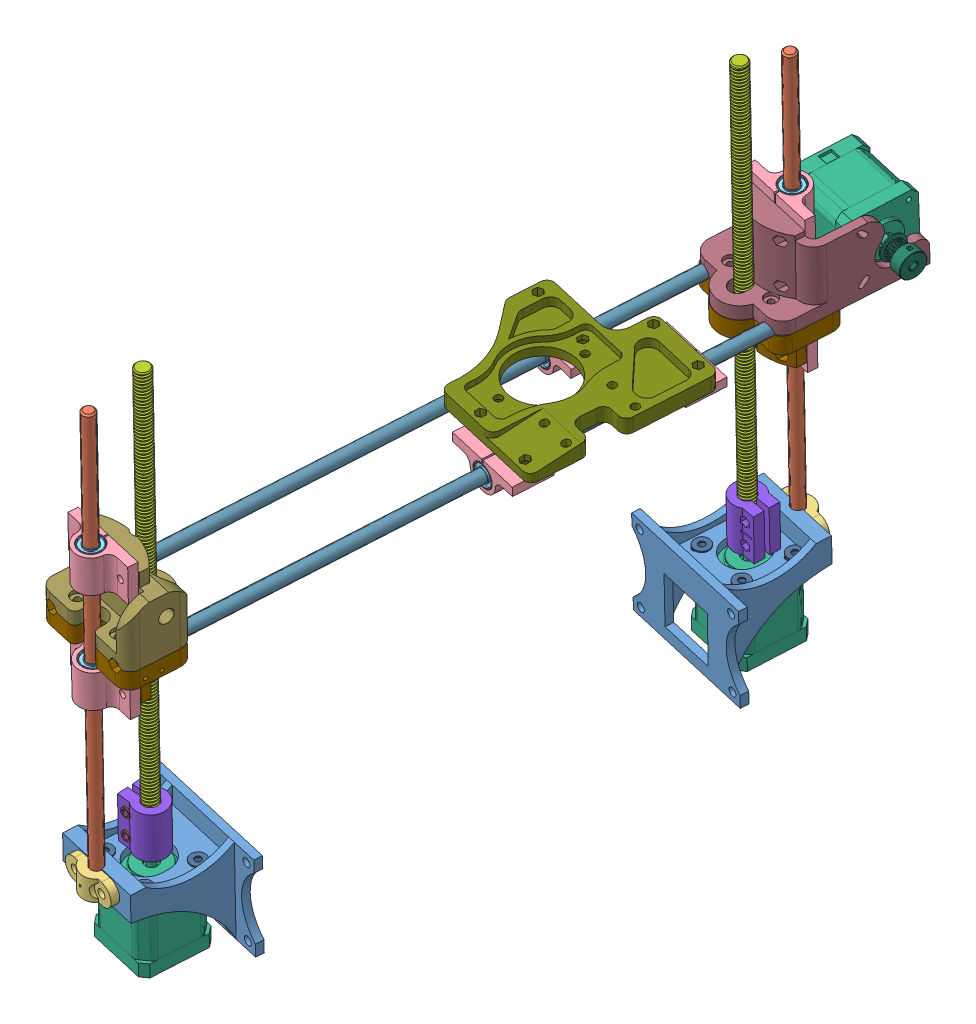
SolidWorks assembly A3, configuration Default. Lengths in mm.
Overall size (186.07 400.02 476.27).
47 component instances, 16 part files, 104 mates.
Components (placement in the parent):
- Lower_Z_Mount_Motor-1: Lower_Z_Mount_Motor [Default] at (-123.1872 -95.1328 92.592) x (0.983752 -0.104217 0.146191) z (-0.155954 -0.092637 0.983411) size (84 62 65)
- Lower_Z_Mount_Motor-2: Lower_Z_Mount_Motor [Default] at (2.3352 -78.4119 -165.566) x (-0.983752 0.104217 -0.146191) z (0.155954 0.092637 -0.983411) size (84 62 65)
- 30.5cm Aluminum rod-1: 30.5cm Aluminum rod [Default] at (-93.3141 -120.0876 161.0751) x (0.947705 -0.117312 0.296804) z (0.088945 0.990231 0.107384) size (8 8 305)
- 30.5cm Aluminum rod-2: 30.5cm Aluminum rod [Default] at (-29.9132 -82.5952 -237.1706) x (-0.920948 0.122827 -0.369821) z (0.088945 0.990231 0.107384) size (8 8 305)
- z_clampNoChange-1: z_clampNoChange [Default] at (-28.8698 -76.5079 -236.4318) x (0.983752 -0.104217 0.146191) z (0.088945 0.990231 0.107384) size (36 10 15)
- z_clampNoChange-2: z_clampNoChange [Default] at (-93.2278 -113.599 161.7) x (-0.983752 0.104217 -0.146191) z (0.088945 0.990231 0.107384) size (36 10 15)
- 100-009-1: 100-009 [Default] at (-57.7405 -0.5492 167.7852) x (-0.983752 0.104217 -0.146191) z (0.155954 0.092637 -0.983411) size (47 24 20.05)
- 100-009-2: 100-009 [Default] at (-43.7387 39.9884 -217.6241) x (0.983752 -0.104217 0.146191) z (-0.155954 -0.092637 0.983411) size (47 24 20.05)
- LM8UU-1: LM8UU [Default] at (-81.3727 12.8561 175.4921) x (-0.088945 -0.990231 -0.107384) z (-0.00782 -0.107114 0.994216) size (24 15 15)
- LM8UU-2: LM8UU [Default] at (-17.9718 50.3486 -222.7537) x (-0.088945 -0.990231 -0.107384) z (-0.00782 -0.107114 0.994216) size (24 15 15)
- Motor - NEMA17 (1)-1: Motor - NEMA17 (1) [Default] at (-88.6025 -120.4512 129.7948) x (0.983752 -0.104217 0.146191) z (0.088945 0.990231 0.107384) size (42 42 71)
- Threaded aluminum rod ACME 98940A303-1: Threaded aluminum rod ACME 98940A303 [98940A303] at (-86.29 -94.7052 132.5868) x (0.088945 0.990231 0.107384) z (-0.053534 -0.102903 0.99325) size (294.74 9.53 11)
- Threaded aluminum rod ACME 98940A303-2: Threaded aluminum rod ACME 98940A303 [98940A303] at (-6.5927 226.5005 -175.2469) x (-0.088945 -0.990231 -0.107384) z (-0.423492 0.135178 -0.895757) size (294.74 9.53 11)
- Motor - NEMA17 (1)-2: Motor - NEMA17 (1) [Default] at (-34.8861 -88.492 -209.4058) x (0.984982 -0.103463 0.138223) z (0.088945 0.990231 0.107384) size (42 42 71)
- Beefey_Coupler_AcmePart-1: Beefey_Coupler_AcmePart [Default] at (-100.0625 -92.4121 131.4893) x (-0.99511 0.092994 -0.033295) z (0.088945 0.990231 0.107384) size (23.96 19.91 30)
- Beefey_Coupler_AcmePart-3: Beefey_Coupler_AcmePart [Default] at (-18.7292 -63.2748 -204.5639) x (0.991285 -0.098523 0.087448) z (0.088945 0.990231 0.107384) size (23.96 19.91 30)
- Ao-X end clamp acme (2_25_2016) (1)-1: Ao-X end clamp acme (2_25_2016) (1) [Default] at (-17.7466 78.2393 -205.8823) x (0.983752 -0.104217 0.146191) z (-0.088945 -0.990231 -0.107384) size (67.8 51.25 34.75)
- Ao-X end clamp acme (2_25_2016) (1)-2: Ao-X end clamp acme (2_25_2016) (1) [Default] at (-76.4758 43.3024 164.9282) x (-0.983752 0.104217 -0.146191) z (-0.088945 -0.990231 -0.107384) size (67.8 51.25 34.75)
- 4.0 washer-1: 4.0 washer [Default] at (-51.8867 -82.0988 -195.6111) x (-0.805696 0.134916 -0.57676) z (-0.088945 -0.990231 -0.107384) size (10 10 0.8)
- 4.0 washer-2: 4.0 washer [Default] at (-21.3522 -85.3061 -191.3261) x (-0.805696 0.134916 -0.57676) z (-0.088945 -0.990231 -0.107384) size (10 10 0.8)
- 4.0 washer-3: 4.0 washer [Default] at (-16.7648 -82.4083 -221.8476) x (-0.805696 0.134916 -0.57676) z (-0.088945 -0.990231 -0.107384) size (10 10 0.8)
- 4.0 washer-4: 4.0 washer [Default] at (-47.2992 -79.201 -226.1325) x (-0.805696 0.134916 -0.57676) z (-0.088945 -0.990231 -0.107384) size (10 10 0.8)
- 4.0 washer-5: 4.0 washer [Default] at (-100.873 -111.1616 112.9625) x (0.991137 -0.098672 0.088945) z (-0.088945 -0.990231 -0.107384) size (10 10 0.8)
- 4.0 washer-6: 4.0 washer [Default] at (-70.3767 -114.3923 117.4944) x (0.991137 -0.098672 0.088945) z (-0.088945 -0.990231 -0.107384) size (10 10 0.8)
- 4.0 washer-7: 4.0 washer [Default] at (-75.2113 -117.264 147.9801) x (0.991137 -0.098672 0.088945) z (-0.088945 -0.990231 -0.107384) size (10 10 0.8)
- 4.0 washer-8: 4.0 washer [Default] at (-105.7076 -114.0333 143.4482) x (-0.805696 0.134916 -0.57676) z (-0.088945 -0.990231 -0.107384) size (10 10 0.8)
- thin 4.0 washers-1: thin 4.0 washers [Default] at (-23.2197 -55.2077 -214.0326) x (0.995256 -0.004817 0.097174) z (-0.097174 -0.09867 0.990364) size (6 6 1)
- thin 4.0 washers-2: thin 4.0 washers [Default] at (-24.5538 -70.0611 -215.6433) x (0.995256 -0.004817 0.097174) z (-0.097174 -0.09867 0.990364) size (6 6 1)
- thin 4.0 washers-3: thin 4.0 washers [Default] at (-93.8089 -87.3768 141.079) x (0.999074 -0.002239 0.042956) z (-0.042956 -0.103898 0.99366) size (6 6 1)
- thin 4.0 washers-4: thin 4.0 washers [Default] at (-95.143 -102.2303 139.4683) x (0.999074 -0.002239 0.042956) z (-0.042956 -0.103898 0.99366) size (6 6 1)
- AO-X end_idle_acme-1: AO-X end_idle_acme [Default] at (-76.2791 43.2816 164.9575) x (-0.983752 0.104217 -0.146191) z (-0.088945 -0.990231 -0.107384) size (68.2 51.25 49.25)
- AO-x-end-motor_acme-1: AO-x-end-motor_acme [Default] at (-17.3868 80.7276 -205.8451) x (-0.983752 0.104217 -0.146191) z (0.088945 0.990231 0.107384) size (68 99 49.25)
- 40.5cm Aluminum rod-1: 40.5cm Aluminum rod [Default] at (8.3866 77.0802 -213.2315) x (0.987688 -0.002259 0.156419) z (-0.155954 -0.092637 0.983411) size (8 8 405)
- 40.5cm Aluminum rod-2: 40.5cm Aluminum rod [Default] at (-39.2187 82.8934 -227.4069) x (0.624684 0.76196 0.170841) z (-0.155954 -0.092637 0.983411) size (8 8 405)
- Motor - NEMA17 (1)-3: Motor - NEMA17 (1) [Default] at (19.7472 104.4291 -243.1976) x (0.157315 0.10799 -0.981626) z (0.983752 -0.104217 0.146191) size (42 42 71)
- 16T Belt Pulley-1: 16T Belt Pulley [Default] at (35.1847 105.3076 -240.923) x (0.983752 -0.104217 0.146191) z (-0.146191 0.00768 0.989227) size (16.47 16 16)
- 100-009-6: 100-009 [Default] at (-81.399 84.186 -99.7077) x (0.97774 -0.155954 0.140364) z (0.140364 0.983411 0.114896) size (47 24 20.05)
- 100-009-7: 100-009 [Default] at (-44.2669 71.3933 -23.8434) x (0.983752 -0.104217 0.146191) z (0.088945 0.990231 0.107384) size (47 24 20.05)
- 100-009-8: 100-009 [Default] at (-28.6716 80.657 -122.1845) x (0.983752 -0.104217 0.146191) z (0.088945 0.990231 0.107384) size (47 24 20.05)
- LM8UU-6: LM8UU [Default] at (-57.9393 71.7734 -109.3591) x (0.155954 0.092637 -0.983411) z (0.140364 0.983411 0.114896) size (24 15 15)
- LM8UU-7: LM8UU [Default] at (-20.1505 60.1291 -33.2824) x (0.155954 0.092637 -0.983411) z (0.140364 0.983411 0.114896) size (24 15 15)
- LM8UU-8: LM8UU [Default] at (-4.5551 69.3928 -131.6235) x (0.155954 0.092637 -0.983411) z (0.140364 0.983411 0.114896) size (24 15 15)
- Stablized x - carriage-2: Stablized x - carriage [Default] at (-13.1593 75.4114 -86.6619) x (-0.155954 -0.092637 0.983411) z (0.088945 0.990231 0.107384) size (110 100 10)
- 100-009-9: 100-009 [Default] at (-51.2119 72.1338 175.6672) x (-0.983752 0.104217 -0.146191) z (0.155954 0.092637 -0.983411) size (47 24 20.05)
- 100-009-10: 100-009 [Default] at (-37.2102 112.6713 -209.7421) x (0.983752 -0.104217 0.146191) z (-0.155954 -0.092637 0.983411) size (47 24 20.05)
- LM8UU-9: LM8UU [Default] at (-11.4432 123.0315 -214.8717) x (0.088945 0.990231 0.107384) z (-0.004799 -0.107384 0.994206) size (24 15 15)
- LM8UU-10: LM8UU [Default] at (-74.8442 85.5391 183.3741) x (0.088945 0.990231 0.107384) z (-0.004799 -0.107384 0.994206) size (24 15 15)
Mates (geometry in assembly coordinates):
- Distance1: distance = 275 mm anti-aligned: plane of Lower_Z_Mount_Motor-1 through (-145.2625 -123.7834 86.3923) normal (0.155954 0.092637 -0.983411); plane of Lower_Z_Mount_Motor-2 through (18.896 -111.1556 -166.0241) normal (-0.155954 -0.092637 0.983411)
- Coincident2: coincident aligned: plane of Lower_Z_Mount_Motor-1 through (-123.9669 -95.596 97.509) normal (0.088945 0.990231 0.107384); plane of Lower_Z_Mount_Motor-2 through (3.115 -77.9487 -170.4831) normal (0.088945 0.990231 0.107384)
- Coincident3: coincident aligned: plane of Lower_Z_Mount_Motor-1 through (-41.3318 -104.3501 109.789) normal (0.983752 -0.104217 0.146191); plane of Lower_Z_Mount_Motor-2 through (3.115 -77.9487 -170.4831) normal (0.983752 -0.104217 0.146191)
- Concentric3: concentric anti-aligned: cylinder of 30.5cm Aluminum rod-1 through (-66.1858 181.9328 193.8274) axis (-0.088945 -0.990231 -0.107384) radius 4; cylinder of z_clampNoChange-2 through (-93.403 -121.0779 160.9677) axis (0.088945 0.990231 0.107384) radius 4.1
- Coincident4: coincident anti-aligned: plane of Lower_Z_Mount_Motor-1 through (-133.3242 -101.1541 156.5137) normal (-0.155954 -0.092637 0.983411); plane of z_clampNoChange-2 through (-93.2278 -113.599 161.7) normal (0.155954 0.092637 -0.983411)
- Concentric6: concentric anti-aligned: cylinder of 30.5cm Aluminum rod-2 through (-2.7849 219.4252 -204.4184) axis (-0.088945 -0.990231 -0.107384) radius 4; cylinder of z_clampNoChange-1 through (-30.0288 -83.8825 -237.3102) axis (0.088945 0.990231 0.107384) radius 4.1
- Coincident6: coincident anti-aligned: plane of Lower_Z_Mount_Motor-2 through (12.4722 -72.3905 -229.4877) normal (0.155954 0.092637 -0.983411); plane of z_clampNoChange-1 through (-28.8698 -76.5079 -236.4318) normal (-0.155954 -0.092637 0.983411)
- Distance13: distance = 1 mm aligned: plane of Lower_Z_Mount_Motor-2 through (3.115 -77.9487 -170.4831) normal (0.088945 0.990231 0.107384); plane of z_clampNoChange-1 through (-26.7212 -68.2011 -244.9688) normal (0.088945 0.990231 0.107384)
- Concentric7: concentric anti-aligned: cylinder of 30.5cm Aluminum rod-2 through (-2.7849 219.4252 -204.4184) axis (-0.088945 -0.990231 -0.107384) radius 4; cylinder of LM8UU-2 through (-13.908 95.5917 -217.8474) axis (0.088945 0.990231 0.107384) radius 4
- Concentric8: concentric anti-aligned: cylinder of 30.5cm Aluminum rod-1 through (-66.1858 181.9328 193.8274) axis (-0.088945 -0.990231 -0.107384) radius 4; cylinder of LM8UU-1 through (-77.3089 58.0993 180.3984) axis (0.088945 0.990231 0.107384) radius 4
- Concentric9: concentric aligned: cylinder of 100-009-2 through (-19.0391 38.4658 -224.0423) axis (0.088945 0.990231 0.107384) radius 7.55; cylinder of LM8UU-2 through (-13.908 95.5917 -217.8474) axis (0.088945 0.990231 0.107384) radius 7.5
- Coincident8: coincident aligned: plane of 100-009-2 through (-4.1382 37.0013 -222.8799) normal (-0.088945 -0.990231 -0.107384); plane of LM8UU-2 through (-19.0391 38.4658 -224.0423) normal (-0.088945 -0.990231 -0.107384)
- Concentric10: concentric aligned: cylinder of 100-009-1 through (-82.4401 0.9734 174.2034) axis (0.088945 0.990231 0.107384) radius 7.55; cylinder of LM8UU-1 through (-77.3089 58.0993 180.3984) axis (0.088945 0.990231 0.107384) radius 7.5
- Coincident9: coincident aligned: plane of 100-009-1 through (-95.2063 26.2034 175.6182) normal (0.088945 0.990231 0.107384); plane of LM8UU-1 through (-80.3054 24.7389 176.7807) normal (0.088945 0.990231 0.107384)
- Coincident12: coincident aligned: plane of 30.5cm Aluminum rod-1 through (-66.1858 181.9328 193.8274) normal (0.088945 0.990231 0.107384); plane of 30.5cm Aluminum rod-2 through (-2.7849 219.4252 -204.4184) normal (0.088945 0.990231 0.107384)
- Distance2: distance = 1 mm aligned: plane of z_clampNoChange-2 through (-95.3765 -121.9058 170.2371) normal (-0.088945 -0.990231 -0.107384); plane of 30.5cm Aluminum rod-1 through (-93.3141 -120.0876 161.0751) normal (-0.088945 -0.990231 -0.107384)
- Coincident19: coincident aligned: plane of 100-009-1 through (-97.341 2.4379 173.041) normal (-0.088945 -0.990231 -0.107384); plane of 100-009-2 through (-4.1382 37.0013 -222.8799) normal (-0.088945 -0.990231 -0.107384)
- Coincident21: coincident anti-aligned: plane of Lower_Z_Mount_Motor-1 through (-134.9252 -118.9783 154.5808) normal (-0.088945 -0.990231 -0.107384); plane of Motor - NEMA17 (1)-1 through (-88.6025 -120.4512 129.7948) normal (0.088945 0.990231 0.107384)
- Parallel13: parallel aligned: plane of Lower_Z_Mount_Motor-1 through (-146.0423 -124.2466 91.3093) normal (-0.155954 -0.092637 0.983411); plane of Motor - NEMA17 (1)-1 through (-79.1534 -170.7283 147.9114) normal (-0.155954 -0.092637 0.983411)
- Concentric16: concentric anti-aligned: circle of Threaded aluminum rod ACME 98940A303-1; cylinder of Beefey_Coupler_AcmePart-1 through (-86.29 -94.7052 132.5868) axis (0.088945 0.990231 0.107384) radius 5
- Parallel15: parallel aligned: cylinder of Motor - NEMA17 (1)-1 through (-86.4678 -96.6857 132.372) axis (-0.088945 -0.990231 -0.107384) radius 2.5; line of Beefey_Coupler_AcmePart-1 through (-88.8956 -94.6203 133.9615) axis (-0.088945 -0.990231 -0.107384)
- Coincident38: coincident aligned: plane of Motor - NEMA17 (1)-1 through (-92.7829 -166.9921 124.7477) normal (-0.088945 -0.990231 -0.107384); plane of Motor - NEMA17 (1)-2 through (-39.0665 -135.0328 -214.4529) normal (-0.088945 -0.990231 -0.107384)
- Distance5: distance = 0.7 mm aligned: plane of Lower_Z_Mount_Motor-1 through (-123.9669 -95.596 97.509) normal (0.088945 0.990231 0.107384); plane of z_clampNoChange-2 through (-94.0423 -107.0523 171.8478) normal (0.088945 0.990231 0.107384)
- Distance4: distance = 13 mm anti-aligned: plane of Beefey_Coupler_AcmePart-1 through (-87.923 -110.3941 138.9268) normal (-0.088945 -0.990231 -0.107384); plane of Motor - NEMA17 (1)-1 through (-86.4678 -96.6857 132.372) normal (0.088945 0.990231 0.107384)
- Coincident49: coincident anti-aligned: plane of Threaded aluminum rod ACME 98940A303-1 through (-86.29 -94.7052 132.5868) normal (-0.088945 -0.990231 -0.107384); plane of Beefey_Coupler_AcmePart-1 through (-86.29 -94.7052 132.5868) normal (0.088945 0.990231 0.107384)
- Concentric37: concentric anti-aligned: circle of Threaded aluminum rod ACME 98940A303-2; cylinder of Beefey_Coupler_AcmePart-3 through (-32.5735 -62.746 -206.6138) axis (0.088945 0.990231 0.107384) radius 5
- Coincident58: coincident anti-aligned: plane of Threaded aluminum rod ACME 98940A303-2 through (-32.5735 -62.746 -206.6138) normal (-0.088945 -0.990231 -0.107384); plane of Beefey_Coupler_AcmePart-3 through (-32.5735 -62.746 -206.6138) normal (0.088945 0.990231 0.107384)
- Parallel20: parallel aligned: plane of 100-009-2 through (-2.0035 60.7668 -220.3027) normal (0.088945 0.990231 0.107384); plane of Ao-X end clamp acme (2_25_2016) (1)-1 through (5.9002 74.4516 -190.5409) normal (0.088945 0.990231 0.107384)
- Slot7: slot anti-aligned: cylinder of Ao-X end clamp acme (2_25_2016) (1)-1 through (-20.0067 76.8977 -191.6295) axis (-0.088945 -0.990231 -0.107384) radius 5.5; cylinder of Threaded aluminum rod ACME 98940A303-2 through (-32.5735 -62.746 -206.6138) axis (0.088945 0.990231 0.107384) radius 4.7625; cylinder of Ao-X end clamp acme (2_25_2016) (1)-1 through (-20.4741 76.6201 -188.6825) axis (-0.088945 -0.990231 -0.107384) radius 5.5
- Coincident65: coincident aligned: plane of 100-009-2 through (-42.803 40.5442 -223.5245) normal (-0.983752 0.104217 -0.146191); plane of Ao-X end clamp acme (2_25_2016) (1)-1 through (-41.7353 68.7847 -210.5771) normal (-0.983752 0.104217 -0.146191)
- Distance8: distance = 6.7 mm aligned: plane of 100-009-2 through (-4.1382 37.0013 -222.8799) normal (-0.088945 -0.990231 -0.107384); plane of Ao-X end clamp acme (2_25_2016) (1)-1 through (2.8093 40.0411 -194.2725) normal (-0.088945 -0.990231 -0.107384)
- Distance9: distance = 6.7 mm aligned: plane of Ao-X end clamp acme (2_25_2016) (1)-2 through (-103.2134 12.6796 145.8552) normal (-0.088945 -0.990231 -0.107384); plane of 100-009-1 through (-97.341 2.4379 173.041) normal (-0.088945 -0.990231 -0.107384)
- Slot9: slot aligned: cylinder of Threaded aluminum rod ACME 98940A303-1 through (-60.3091 194.5412 163.9537) axis (-0.088945 -0.990231 -0.107384) radius 4.7625; cylinder of Ao-X end clamp acme (2_25_2016) (1)-2 through (-74.2155 44.646 150.6757) axis (-0.088945 -0.990231 -0.107384) radius 5.5; cylinder of Ao-X end clamp acme (2_25_2016) (1)-2 through (-73.7481 44.9236 147.7286) axis (-0.088945 -0.990231 -0.107384) radius 5.5
- Distance10: distance = 0.5 mm anti-aligned: plane of 100-009-2 through (-43.7387 39.9884 -217.6241) normal (-0.155954 -0.092637 0.983411); plane of Ao-X end clamp acme (2_25_2016) (1)-1 through (-18.2759 66.6761 -210.5637) normal (0.155954 0.092637 -0.983411)
- Parallel24: parallel anti-aligned: plane of 100-009-1 through (-57.7405 -0.5492 167.7852) normal (0.155954 0.092637 -0.983411); plane of Ao-X end clamp acme (2_25_2016) (1)-2 through (-78.0812 31.1 167.0324) normal (-0.155954 -0.092637 0.983411)
- Distance11: distance = 0.5 mm anti-aligned: plane of Ao-X end clamp acme (2_25_2016) (1)-2 through (-78.0812 31.1 167.0324) normal (-0.155954 -0.092637 0.983411); plane of 100-009-1 through (-57.7405 -0.5492 167.7852) normal (0.155954 0.092637 -0.983411)
- Parallel29: parallel aligned: plane of Lower_Z_Mount_Motor-1 through (-41.3318 -104.3501 109.789) normal (0.983752 -0.104217 0.146191); plane of 100-009-1 through (-58.6762 -1.105 173.6857) normal (0.983752 -0.104217 0.146191)
- Parallel30: parallel aligned: plane of 100-009-1 through (-103.9768 4.349 160.9142) normal (-0.983752 0.104217 -0.146191); plane of Ao-X end clamp acme (2_25_2016) (1)-2 through (-100.8581 33.8896 160.1749) normal (-0.983752 0.104217 -0.146191)
- Concentric45: concentric anti-aligned: circle of Motor - NEMA17 (1)-1; circle of Threaded aluminum rod ACME 98940A303-1
- Concentric46: concentric anti-aligned: cylinder of Lower_Z_Mount_Motor-1 through (-109.2824 -297.8637 141.7964) axis (0.088945 0.990231 0.107384) radius 4; cylinder of 30.5cm Aluminum rod-1 through (-66.1858 181.9328 193.8274) axis (-0.088945 -0.990231 -0.107384) radius 4
- Concentric47: concentric anti-aligned: circle of Threaded aluminum rod ACME 98940A303-2; circle of Motor - NEMA17 (1)-2
- Distance12: distance = 2 mm anti-aligned: plane of Motor - NEMA17 (1)-2 through (-32.7514 -64.7265 -206.8286) normal (0.088945 0.990231 0.107384); plane of Threaded aluminum rod ACME 98940A303-2 through (-32.5735 -62.746 -206.6138) normal (-0.088945 -0.990231 -0.107384)
- Parallel33: parallel aligned: plane of Lower_Z_Mount_Motor-2 through (3.115 -77.9487 -170.4831) normal (0.983752 -0.104217 0.146191); plane of Ao-X end clamp acme (2_25_2016) (1)-1 through (14.3442 41.3843 -216.2131) normal (0.983752 -0.104217 0.146191)
- Parallel34: parallel aligned: plane of Lower_Z_Mount_Motor-1 through (-41.3318 -104.3501 109.789) normal (0.983752 -0.104217 0.146191); plane of Ao-X end clamp acme (2_25_2016) (1)-2 through (-48.0499 4.2705 177.7076) normal (0.983752 -0.104217 0.146191)
- Coincident94: coincident anti-aligned: plane of Lower_Z_Mount_Motor-2 through (1.2234 -90.7898 -166.9083) normal (0.088945 0.990231 0.107384); plane of 4.0 washer-1 through (-51.9579 -82.8909 -195.697) normal (-0.088945 -0.990231 -0.107384)
- Coincident95: coincident anti-aligned: plane of Lower_Z_Mount_Motor-2 through (1.2234 -90.7898 -166.9083) normal (0.088945 0.990231 0.107384); plane of 4.0 washer-2 through (-21.4234 -86.0983 -191.4121) normal (-0.088945 -0.990231 -0.107384)
- Coincident96: coincident anti-aligned: plane of Lower_Z_Mount_Motor-2 through (1.2234 -90.7898 -166.9083) normal (0.088945 0.990231 0.107384); plane of 4.0 washer-3 through (-16.8359 -83.2005 -221.9335) normal (-0.088945 -0.990231 -0.107384)
- Coincident97: coincident anti-aligned: plane of Lower_Z_Mount_Motor-2 through (1.2234 -90.7898 -166.9083) normal (0.088945 0.990231 0.107384); plane of 4.0 washer-4 through (-47.3704 -79.9931 -226.2184) normal (-0.088945 -0.990231 -0.107384)
- Coincident109: coincident anti-aligned: plane of Lower_Z_Mount_Motor-1 through (-124.299 -107.5107 91.2497) normal (0.088945 0.990231 0.107384); plane of 4.0 washer-8 through (-105.7788 -114.8255 143.3623) normal (-0.088945 -0.990231 -0.107384)
- Coincident110: coincident anti-aligned: plane of Lower_Z_Mount_Motor-1 through (-124.299 -107.5107 91.2497) normal (0.088945 0.990231 0.107384); plane of 4.0 washer-7 through (-75.2825 -118.0562 147.8942) normal (-0.088945 -0.990231 -0.107384)
- Coincident111: coincident anti-aligned: plane of Lower_Z_Mount_Motor-1 through (-124.299 -107.5107 91.2497) normal (0.088945 0.990231 0.107384); plane of 4.0 washer-6 through (-70.4479 -115.1845 117.4085) normal (-0.088945 -0.990231 -0.107384)
- Coincident112: coincident anti-aligned: plane of Lower_Z_Mount_Motor-1 through (-124.299 -107.5107 91.2497) normal (0.088945 0.990231 0.107384); plane of 4.0 washer-5 through (-100.9442 -111.9537 112.8766) normal (-0.088945 -0.990231 -0.107384)
- Coincident115: coincident anti-aligned: plane of Beefey_Coupler_AcmePart-3 through (-30.5066 -47.0987 -212.9299) normal (0.097174 0.09867 -0.990364); plane of thin 4.0 washers-1 through (-23.3168 -55.3063 -213.0422) normal (-0.097174 -0.09867 0.990364)
- Concentric73: concentric anti-aligned: cylinder of Beefey_Coupler_AcmePart-3 through (-23.1269 -55.1134 -214.9784) axis (-0.097174 -0.09867 0.990364) radius 2; cylinder of thin 4.0 washers-1 through (-23.3168 -55.3063 -213.0422) axis (0.097174 0.09867 -0.990364) radius 2.025
- Coincident116: coincident anti-aligned: plane of Beefey_Coupler_AcmePart-3 through (-30.5066 -47.0987 -212.9299) normal (0.097174 0.09867 -0.990364); plane of thin 4.0 washers-2 through (-24.651 -70.1598 -214.653) normal (-0.097174 -0.09867 0.990364)
- Concentric74: concentric anti-aligned: cylinder of Beefey_Coupler_AcmePart-3 through (-24.461 -69.9669 -216.5891) axis (-0.097174 -0.09867 0.990364) radius 2; cylinder of thin 4.0 washers-2 through (-24.651 -70.1598 -214.653) axis (0.097174 0.09867 -0.990364) radius 2.025
- Coincident117: coincident anti-aligned: plane of Beefey_Coupler_AcmePart-1 through (-85.2546 -80.6871 142.1483) normal (-0.042956 -0.103898 0.99366); plane of thin 4.0 washers-3 through (-93.8089 -87.3768 141.079) normal (0.042956 0.103898 -0.99366)
- Concentric75: concentric aligned: cylinder of Beefey_Coupler_AcmePart-1 through (-93.8928 -87.5799 143.0216) axis (0.042956 0.103898 -0.99366) radius 2; cylinder of thin 4.0 washers-3 through (-93.8518 -87.4807 142.0727) axis (0.042956 0.103898 -0.99366) radius 2.025
- Concentric76: concentric aligned: cylinder of Beefey_Coupler_AcmePart-1 through (-95.227 -102.4334 141.4109) axis (0.042956 0.103898 -0.99366) radius 2; cylinder of thin 4.0 washers-4 through (-95.186 -102.3342 140.4619) axis (0.042956 0.103898 -0.99366) radius 2.025
- Coincident118: coincident anti-aligned: plane of Beefey_Coupler_AcmePart-1 through (-85.2546 -80.6871 142.1483) normal (-0.042956 -0.103898 0.99366); plane of thin 4.0 washers-4 through (-95.143 -102.2303 139.4683) normal (0.042956 0.103898 -0.99366)
- Coincident119: coincident anti-aligned: plane of Ao-X end clamp acme (2_25_2016) (1)-2 through (-100.1225 47.0901 149.5868) normal (0.088945 0.990231 0.107384); plane of AO-X end_idle_acme-1 through (-76.2791 43.2816 164.9575) normal (-0.088945 -0.990231 -0.107384)
- Coincident120: coincident aligned: plane of Ao-X end clamp acme (2_25_2016) (1)-2 through (-57.1676 4.3631 184.4053) normal (-0.155954 -0.092637 0.983411); plane of AO-X end_idle_acme-1 through (-74.9786 90.2209 189.6685) normal (-0.155954 -0.092637 0.983411)
- Coincident121: coincident aligned: plane of Ao-X end clamp acme (2_25_2016) (1)-2 through (-114.7483 11.3363 167.7958) normal (-0.983752 0.104217 -0.146191); plane of AO-X end_idle_acme-1 through (-105.4445 95.6042 165.261) normal (-0.983752 0.104217 -0.146191)
- Coincident122: coincident anti-aligned: plane of Ao-X end clamp acme (2_25_2016) (1)-1 through (5.9002 74.4516 -190.5409) normal (0.088945 0.990231 0.107384); plane of AO-x-end-motor_acme-1 through (-17.6092 78.252 -206.1135) normal (-0.088945 -0.990231 -0.107384)
- Coincident124: coincident aligned: plane of Ao-X end clamp acme (2_25_2016) (1)-1 through (-49.3966 44.6984 -193.9779) normal (-0.155954 -0.092637 0.983411); plane of AO-x-end-motor_acme-1 through (-20.7283 76.3993 -186.4453) normal (-0.155954 -0.092637 0.983411)
- Tangent1: tangent anti-aligned: plane of Ao-X end clamp acme (2_25_2016) (1)-1 through (-43.5561 83.1294 -229.5978) normal (0.856859 0.482604 0.181345); cylinder of 40.5cm Aluminum rod-2 through (-102.38 45.3756 170.8745) axis (0.155954 0.092637 -0.983411) radius 4
- Tangent2: tangent anti-aligned: plane of Ao-X end clamp acme (2_25_2016) (1)-1 through (-37.5001 78.6091 -229.0632) normal (-0.754825 0.653342 -0.058159); cylinder of 40.5cm Aluminum rod-2 through (-102.38 45.3756 170.8745) axis (0.155954 0.092637 -0.983411) radius 4
- Distance14: distance = 2 mm aligned: plane of 40.5cm Aluminum rod-2 through (-39.2187 82.8934 -227.4069) normal (0.155954 0.092637 -0.983411); plane of AO-x-end-motor_acme-1 through (-14.4901 80.1047 -225.7817) normal (0.155954 0.092637 -0.983411)
- Tangent3: tangent anti-aligned: plane of Ao-X end clamp acme (2_25_2016) (1)-1 through (14.2232 77.0083 -221.0115) normal (-0.754825 0.653342 -0.058159); cylinder of 40.5cm Aluminum rod-1 through (-54.7746 39.5623 185.0499) axis (0.155954 0.092637 -0.983411) radius 4
- Tangent4: tangent anti-aligned: plane of Ao-X end clamp acme (2_25_2016) (1)-1 through (7.477 73.8444 -222.3794) normal (0.856859 0.482604 0.181345); cylinder of 40.5cm Aluminum rod-1 through (-54.7746 39.5623 185.0499) axis (0.155954 0.092637 -0.983411) radius 4
- Distance15: distance = 3 mm aligned: plane of 40.5cm Aluminum rod-1 through (-54.7746 39.5623 185.0499) normal (-0.155954 -0.092637 0.983411); plane of Ao-X end clamp acme (2_25_2016) (1)-2 through (-57.1676 4.3631 184.4053) normal (-0.155954 -0.092637 0.983411)
- Coincident125: coincident anti-aligned: plane of AO-x-end-motor_acme-1 through (14.6176 120.822 -196.9928) normal (-0.983752 0.104217 -0.146191); plane of Motor - NEMA17 (1)-3 through (19.7472 104.4291 -243.1976) normal (0.983752 -0.104217 0.146191)
- Concentric82: concentric aligned: cylinder of Motor - NEMA17 (1)-3 through (43.3573 101.9279 -239.689) axis (-0.983752 0.104217 -0.146191) radius 2.5; cylinder of 16T Belt Pulley-1 through (27.6172 103.5954 -242.0281) axis (-0.983752 0.104217 -0.146191) radius 2.5
- Coincident129: coincident aligned: plane of Motor - NEMA17 (1)-3 through (43.3573 101.9279 -239.689) normal (0.983752 -0.104217 0.146191); plane of 16T Belt Pulley-1 through (43.6178 104.4142 -239.6698) normal (0.983752 -0.104217 0.146191)
- Slot10: slot aligned: plane of AO-x-end-motor_acme-1 through (-43.1138 121.8645 -235.9694) normal (0.171454 0.786888 -0.592799); cylinder of Motor - NEMA17 (1)-3 through (14.2229 118.5487 -226.7395) axis (0.983752 -0.104217 0.146191) radius 1.5; cylinder of AO-x-end-motor_acme-1 through (-43.0268 125.6744 -233.8389) axis (0.983752 -0.104217 0.146191) radius 1.75
- Slot11: slot aligned: cylinder of AO-x-end-motor_acme-1 through (-45.9267 92.5242 -237.957) axis (0.983752 -0.104217 0.146191) radius 1.75; cylinder of Motor - NEMA17 (1)-3 through (11.541 87.8998 -230.541) axis (0.983752 -0.104217 0.146191) radius 1.5; cylinder of AO-x-end-motor_acme-1 through (-45.2409 95.6717 -240.3282) axis (0.983752 -0.104217 0.146191) radius 1.75
- Slot12: slot aligned: cylinder of AO-x-end-motor_acme-1 through (-40.8166 98.1981 -268.299) axis (0.983752 -0.104217 0.146191) radius 1.75; cylinder of Motor - NEMA17 (1)-3 through (16.4178 91.2475 -260.9714) axis (0.983752 -0.104217 0.146191) radius 1.5; cylinder of AO-x-end-motor_acme-1 through (-40.6036 95.7652 -271.4668) axis (0.983752 -0.104217 0.146191) radius 1.75
- Coincident142: coincident aligned: plane of Ao-X end clamp acme (2_25_2016) (1)-1 through (-52.3541 48.4502 -226.1248) normal (-0.983752 0.104217 -0.146191); plane of AO-x-end-motor_acme-1 through (-51.0567 81.7954 -211.084) normal (-0.983752 0.104217 -0.146191)
- Concentric94: concentric anti-aligned: cylinder of 100-009-8 through (-6.4265 68.2811 -119.8226) axis (0.155954 0.092637 -0.983411) radius 7.55; cylinder of LM8UU-8 through (-11.6806 65.1602 -86.6919) axis (-0.155954 -0.092637 0.983411) radius 7.5
- Concentric95: concentric anti-aligned: cylinder of 100-009-7 through (-22.0219 59.0174 -21.4815) axis (0.155954 0.092637 -0.983411) radius 7.55; cylinder of LM8UU-7 through (-27.2759 55.8966 11.6491) axis (-0.155954 -0.092637 0.983411) radius 7.5
- Concentric96: concentric anti-aligned: cylinder of 100-009-6 through (-59.8107 70.6618 -97.5581) axis (0.155954 0.092637 -0.983411) radius 7.55; cylinder of LM8UU-6 through (-65.0647 67.5409 -64.4275) axis (-0.155954 -0.092637 0.983411) radius 7.5
- Coincident144: coincident aligned: plane of 100-009-8 through (11.9613 67.9083 -141.3465) normal (0.155954 0.092637 -0.983411); plane of LM8UU-8 through (-2.6837 70.5044 -143.4244) normal (0.155954 0.092637 -0.983411)
- Coincident145: coincident aligned: plane of 100-009-7 through (-3.634 58.6446 -43.0054) normal (0.155954 0.092637 -0.983411); plane of LM8UU-7 through (-18.279 61.2407 -45.0833) normal (0.155954 0.092637 -0.983411)
- Coincident146: coincident aligned: plane of 100-009-6 through (-41.5666 69.521 -119.1772) normal (0.155954 0.092637 -0.983411); plane of LM8UU-6 through (-56.0678 72.8851 -121.16) normal (0.155954 0.092637 -0.983411)
- Concentric97: concentric anti-aligned: cylinder of 40.5cm Aluminum rod-1 through (-54.7746 39.5623 185.0499) axis (0.155954 0.092637 -0.983411) radius 4; cylinder of LM8UU-7 through (-27.2759 55.8966 11.6491) axis (-0.155954 -0.092637 0.983411) radius 4
- Concentric98: concentric anti-aligned: cylinder of 40.5cm Aluminum rod-1 through (-54.7746 39.5623 185.0499) axis (0.155954 0.092637 -0.983411) radius 4; cylinder of LM8UU-8 through (-11.6806 65.1602 -86.6919) axis (-0.155954 -0.092637 0.983411) radius 4
- Concentric99: concentric anti-aligned: cylinder of 40.5cm Aluminum rod-2 through (-102.38 45.3756 170.8745) axis (0.155954 0.092637 -0.983411) radius 4; cylinder of LM8UU-6 through (-65.0647 67.5409 -64.4275) axis (-0.155954 -0.092637 0.983411) radius 4
- Coincident147: coincident anti-aligned: plane of 100-009-7 through (-44.2669 71.3933 -23.8434) normal (0.088945 0.990231 0.107384); plane of Stablized x - carriage-2 through (18.4524 76.9746 -127.2607) normal (-0.088945 -0.990231 -0.107384)
- Parallel38: parallel aligned: plane of Lower_Z_Mount_Motor-2 through (-2.3996 -139.343 -177.1409) normal (-0.088945 -0.990231 -0.107384); plane of Stablized x - carriage-2 through (18.4524 76.9746 -127.2607) normal (-0.088945 -0.990231 -0.107384)
- Distance18: distance = 7 mm aligned: plane of 100-009-7 through (-7.3769 56.4213 -19.4036) normal (-0.155954 -0.092637 0.983411); plane of Stablized x - carriage-2 through (-56.0703 83.4044 -31.7019) normal (-0.155954 -0.092637 0.983411)
- Distance19: distance = 2 mm aligned: plane of 100-009-6 through (-41.5666 69.521 -119.1772) normal (0.155954 0.092637 -0.983411); plane of Stablized x - carriage-2 through (-37.8835 90.7561 -114.5591) normal (0.155954 0.092637 -0.983411)
- Coincident151: coincident anti-aligned: plane of 100-009-8 through (-28.6716 80.657 -122.1845) normal (0.088945 0.990231 0.107384); plane of Stablized x - carriage-2 through (18.4524 76.9746 -127.2607) normal (-0.088945 -0.990231 -0.107384)
- Concentric102: concentric aligned: cylinder of 100-009-8 through (13 71.5543 -128.6359) axis (-0.088945 -0.990231 -0.107384) radius 2.25; cylinder of Stablized x - carriage-2 through (14.4231 87.398 -126.9178) axis (-0.088945 -0.990231 -0.107384) radius 2.5
- Concentric103: concentric aligned: cylinder of 100-009-8 through (-21.4313 75.2019 -133.7526) axis (-0.088945 -0.990231 -0.107384) radius 2.25; cylinder of Stablized x - carriage-2 through (-20.0082 91.0456 -132.0344) axis (-0.088945 -0.990231 -0.107384) radius 2.5
- Concentric104: concentric anti-aligned: cylinder of 100-009-10 through (-12.5106 111.1488 -216.1603) axis (0.088945 0.990231 0.107384) radius 7.55; cylinder of LM8UU-9 through (-15.5071 77.7884 -219.778) axis (-0.088945 -0.990231 -0.107384) radius 7.5
- Concentric105: concentric anti-aligned: cylinder of 100-009-9 through (-75.9115 73.6563 182.0855) axis (0.088945 0.990231 0.107384) radius 7.55; cylinder of LM8UU-10 through (-78.908 40.2959 178.4677) axis (-0.088945 -0.990231 -0.107384) radius 7.5
- Coincident152: coincident aligned: plane of 100-009-9 through (-88.6777 98.8864 183.5002) normal (0.088945 0.990231 0.107384); plane of LM8UU-10 through (-73.7768 97.4219 184.6627) normal (0.088945 0.990231 0.107384)
- Concentric106: concentric aligned: cylinder of 30.5cm Aluminum rod-1 through (-66.1858 181.9328 193.8274) axis (-0.088945 -0.990231 -0.107384) radius 4; cylinder of LM8UU-10 through (-78.908 40.2959 178.4677) axis (-0.088945 -0.990231 -0.107384) radius 4
- Parallel39: parallel anti-aligned: plane of AO-X end_idle_acme-1 through (-76.0166 51.874 169.3167) normal (-0.155954 -0.092637 0.983411); plane of 100-009-9 through (-51.2119 72.1338 175.6672) normal (0.155954 0.092637 -0.983411)
- Distance20: distance = 6.7 mm aligned: plane of 100-009-9 through (-88.6777 98.8864 183.5002) normal (0.088945 0.990231 0.107384); plane of AO-X end_idle_acme-1 through (-71.8985 92.0504 170.2461) normal (0.088945 0.990231 0.107384)
- Coincident154: coincident aligned: plane of 100-009-10 through (4.525 133.4498 -212.4207) normal (0.088945 0.990231 0.107384); plane of LM8UU-9 through (-10.3759 134.9143 -213.5831) normal (0.088945 0.990231 0.107384)
- Concentric107: concentric aligned: cylinder of 30.5cm Aluminum rod-2 through (-2.7849 219.4252 -204.4184) axis (-0.088945 -0.990231 -0.107384) radius 4; cylinder of LM8UU-9 through (-15.5071 77.7884 -219.778) axis (-0.088945 -0.990231 -0.107384) radius 4
- Parallel40: parallel anti-aligned: plane of AO-x-end-motor_acme-1 through (-12.6516 127.3636 -204.4635) normal (0.155954 0.092637 -0.983411); plane of 100-009-10 through (-37.2102 112.6713 -209.7421) normal (-0.155954 -0.092637 0.983411)
- Distance21: distance = 6.7 mm aligned: plane of 100-009-10 through (4.525 133.4498 -212.4207) normal (0.088945 0.990231 0.107384); plane of AO-x-end-motor_acme-1 through (-13.2286 127.0209 -200.8248) normal (0.088945 0.990231 0.107384)
